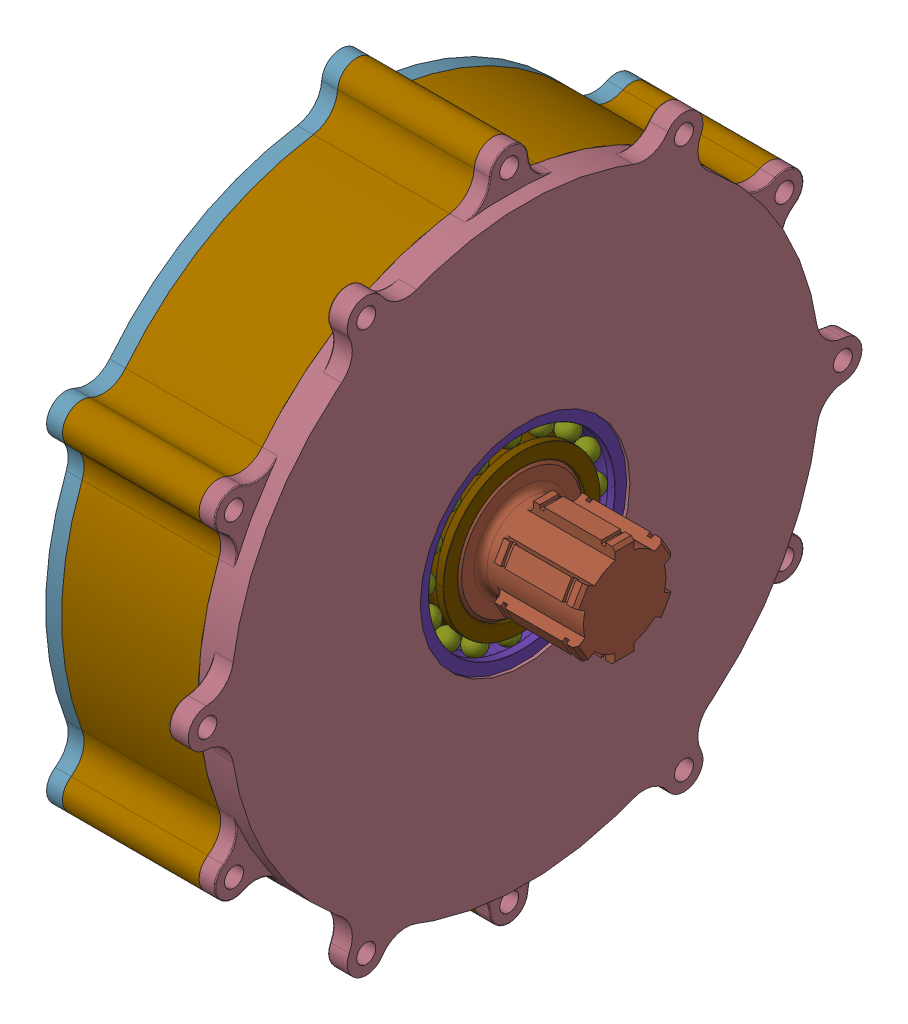
SolidWorks assembly A2490_Planetary_Gear_Set_Assembly, configuration 預設. Lengths in mm.
Overall size (102.6 212 212).
192 component instances, 24 part files, 41 mates.
Components (placement in the parent):
- planetary_gear_layout-1: planetary_gear_layout [預設] at origin
- A2490_Sun_Gear-1: A2490_Sun_Gear [預設] x (1 0 0) z (0 -0.792814 -0.609463) size (61.05 62.36 62.44)
- planet_gear_assembly-1: planet_gear_assembly [預設] at (0 56.25 0) x (1 0 0) z (0 0.754751 -0.656012) size (41 59.98 59.9)
  - A2490_Planet_Gear-1: A2490_Planet_Gear [預設] at origin size (30 59.98 59.9)
  - SKF_609-1: SKF_609 [Default] at (20.15 0 0) x (1 0 0) z (0 0.084929 0.996387) size (7 24 24)
    - SKF_609_12-1: SKF_609_12 [Default] x (1 0 0) z (0 -0.707107 0.707107) size (3.97 3.97 3.97)
    - SKF_609_12-2: SKF_609_12 [Default] x (1 0 0) z (0 -1 0) size (3.97 3.97 3.97)
    - SKF_609_12-3: SKF_609_12 [Default] x (1 0 0) z (0 -0.707107 -0.707107) size (3.97 3.97 3.97)
    - SKF_609_12-4: SKF_609_12 [Default] x (1 0 0) z (0 0 -1) size (3.97 3.97 3.97)
    - SKF_609_12-5: SKF_609_12 [Default] x (1 0 0) z (0 0.707107 -0.707107) size (3.97 3.97 3.97)
    - SKF_609_12-6: SKF_609_12 [Default] x (1 0 0) z (0 1 0) size (3.97 3.97 3.97)
    - SKF_609_12-7: SKF_609_12 [Default] x (1 0 0) z (0 0.707107 0.707107) size (3.97 3.97 3.97)
    - SKF_609_12-8: SKF_609_12 [Default] at origin size (3.97 3.97 3.97)
    - SKF_609_21-1: SKF_609_21 [Default] at origin size (7 24 24)
    - SKF_609_23-1: SKF_609_23 [Default] at origin size (7 14.45 14.45)
  - SKF_609-2: SKF_609 [Default] at (2.85 0 0) x (1 0 0) z (0 -0.037051 0.999313) size (7 24 24)
    - SKF_609_12-1: SKF_609_12 [Default] x (1 0 0) z (0 -0.707107 0.707107) size (3.97 3.97 3.97)
    - SKF_609_12-2: SKF_609_12 [Default] x (1 0 0) z (0 -1 0) size (3.97 3.97 3.97)
    - SKF_609_12-3: SKF_609_12 [Default] x (1 0 0) z (0 -0.707107 -0.707107) size (3.97 3.97 3.97)
    - SKF_609_12-4: SKF_609_12 [Default] x (1 0 0) z (0 0 -1) size (3.97 3.97 3.97)
    - SKF_609_12-5: SKF_609_12 [Default] x (1 0 0) z (0 0.707107 -0.707107) size (3.97 3.97 3.97)
    - SKF_609_12-6: SKF_609_12 [Default] x (1 0 0) z (0 1 0) size (3.97 3.97 3.97)
    - SKF_609_12-7: SKF_609_12 [Default] x (1 0 0) z (0 0.707107 0.707107) size (3.97 3.97 3.97)
    - SKF_609_12-8: SKF_609_12 [Default] at origin size (3.97 3.97 3.97)
    - SKF_609_21-1: SKF_609_21 [Default] at origin size (7 24 24)
    - SKF_609_23-1: SKF_609_23 [Default] at origin size (7 14.45 14.45)
  - WA701_retainingRing-1: WA701_retainingRing [預設] at (27.15 0 0) x (0 0 -1) z (1 0 0) size (25.9 24.75 1.2)
  - WA701_retainingRing-2: WA701_retainingRing [預設] at (1.65 0 0) x (0 0 -1) z (1 0 0) size (25.9 24.75 1.2)
  - A2490_Planet_Shaft-1: A2490_Planet_Shaft [預設] at (15 0 0) x (0 0 -1) z (1 0 0) size (11 11 41)
  - A2490_Planet_Spacer-1: A2490_Planet_Spacer [預設] at (27.15 0 0) x (0 -0.101105 -0.994876) z (1 0 0) size (12 12 3.85)
  - A2490_Planet_Spacer-2: A2490_Planet_Spacer [預設] at (-1 0 0) x (0 -0.111073 -0.993812) z (1 0 0) size (12 12 3.85)
- A2490_Ring_Housing-1: A2490_Ring_Housing [預設] at origin size (43 212 185.75)
- A2490_Carrier_Internal-1: A2490_Carrier_Internal [預設] at (-1 0 0) size (5 132.5 132.5)
- A2490_Carrier_Output-1: A2490_Carrier_Output [預設] at origin size (46.35 132.5 132.5)
- A2490_Carrer_Bridge-1: A2490_Carrer_Bridge [預設] at (15 28.125 -48.7139) size (32.6 16 16)
- A2490_Cap_Output-1: A2490_Cap_Output [預設] at origin size (15.8 212 212)
- A2490_Cap_Input-1: A2490_Cap_Input [預設] at origin size (10.8 212 185.75)
- A2490_Sun_Bearing_Spacer-1: A2490_Sun_Bearing_Spacer [預設] at (-7 0 0) size (2 27 27)
- SKF_16008-2: SKF_16008 [Default] at (36 0 0) size (9 68 68)
  - SKF_16008_20-1: SKF_16008_20 [Default] x (1 0 0) z (0 -0.382683 0.92388) size (6.35 6.35 6.35)
  - SKF_16008_20-2: SKF_16008_20 [Default] x (1 0 0) z (0 -0.707107 0.707107) size (6.35 6.35 6.35)
  - SKF_16008_20-3: SKF_16008_20 [Default] x (1 0 0) z (0 -0.92388 0.382683) size (6.35 6.35 6.35)
  - SKF_16008_20-4: SKF_16008_20 [Default] x (1 0 0) z (0 -1 0) size (6.35 6.35 6.35)
  - SKF_16008_20-5: SKF_16008_20 [Default] x (1 0 0) z (0 -0.92388 -0.382683) size (6.35 6.35 6.35)
  - SKF_16008_20-6: SKF_16008_20 [Default] x (1 0 0) z (0 -0.707107 -0.707107) size (6.35 6.35 6.35)
  - SKF_16008_20-7: SKF_16008_20 [Default] x (1 0 0) z (0 -0.382683 -0.92388) size (6.35 6.35 6.35)
  - SKF_16008_20-8: SKF_16008_20 [Default] x (1 0 0) z (0 0 -1) size (6.35 6.35 6.35)
  - SKF_16008_20-9: SKF_16008_20 [Default] x (1 0 0) z (0 0.382683 -0.92388) size (6.35 6.35 6.35)
  - SKF_16008_20-10: SKF_16008_20 [Default] x (1 0 0) z (0 0.707107 -0.707107) size (6.35 6.35 6.35)
  - SKF_16008_20-11: SKF_16008_20 [Default] x (1 0 0) z (0 0.92388 -0.382683) size (6.35 6.35 6.35)
  - SKF_16008_20-12: SKF_16008_20 [Default] x (1 0 0) z (0 1 0) size (6.35 6.35 6.35)
  - SKF_16008_20-13: SKF_16008_20 [Default] x (1 0 0) z (0 0.92388 0.382683) size (6.35 6.35 6.35)
  - SKF_16008_20-14: SKF_16008_20 [Default] x (1 0 0) z (0 0.707107 0.707107) size (6.35 6.35 6.35)
  - SKF_16008_20-15: SKF_16008_20 [Default] x (1 0 0) z (0 0.382683 0.92388) size (6.35 6.35 6.35)
  - SKF_16008_20-16: SKF_16008_20 [Default] at origin size (6.35 6.35 6.35)
  - SKF_16008_37-1: SKF_16008_37 [Default] at origin size (9 68 68)
  - SKF_16008_39-1: SKF_16008_39 [Default] at origin size (9 49.4 49.4)
- SKF_W_61705-1: SKF_W_61705 [Default] at (-5 0 0) x (1 0 0) z (0 0.081277 0.996692) size (4 32 32)
  - SKF_W_61705_25-1: SKF_W_61705_25 [Default] x (1 0 0) z (0 -0.294755 0.955573) size (1.59 1.59 1.59)
  - SKF_W_61705_25-2: SKF_W_61705_25 [Default] x (1 0 0) z (0 -0.56332 0.826239) size (1.59 1.59 1.59)
  - SKF_W_61705_25-3: SKF_W_61705_25 [Default] x (1 0 0) z (0 -0.781831 0.62349) size (1.59 1.59 1.59)
  - SKF_W_61705_25-4: SKF_W_61705_25 [Default] x (1 0 0) z (0 -0.930874 0.365341) size (1.59 1.59 1.59)
  - SKF_W_61705_25-5: SKF_W_61705_25 [Default] x (1 0 0) z (0 -0.997204 0.07473) size (1.59 1.59 1.59)
  - SKF_W_61705_25-6: SKF_W_61705_25 [Default] x (1 0 0) z (0 -0.974928 -0.222521) size (1.59 1.59 1.59)
  - SKF_W_61705_25-7: SKF_W_61705_25 [Default] x (1 0 0) z (0 -0.866025 -0.5) size (1.59 1.59 1.59)
  - SKF_W_61705_25-8: SKF_W_61705_25 [Default] x (1 0 0) z (0 -0.680173 -0.733052) size (1.59 1.59 1.59)
  - SKF_W_61705_25-9: SKF_W_61705_25 [Default] x (1 0 0) z (0 -0.433884 -0.900969) size (1.59 1.59 1.59)
  - SKF_W_61705_25-10: SKF_W_61705_25 [Default] x (1 0 0) z (0 -0.149042 -0.988831) size (1.59 1.59 1.59)
  - SKF_W_61705_25-11: SKF_W_61705_25 [Default] x (1 0 0) z (0 0.149042 -0.988831) size (1.59 1.59 1.59)
  - SKF_W_61705_25-12: SKF_W_61705_25 [Default] x (1 0 0) z (0 0.433884 -0.900969) size (1.59 1.59 1.59)
  - SKF_W_61705_25-13: SKF_W_61705_25 [Default] x (1 0 0) z (0 0.680173 -0.733052) size (1.59 1.59 1.59)
  - SKF_W_61705_25-14: SKF_W_61705_25 [Default] x (1 0 0) z (0 0.866025 -0.5) size (1.59 1.59 1.59)
  - SKF_W_61705_25-15: SKF_W_61705_25 [Default] x (1 0 0) z (0 0.974928 -0.222521) size (1.59 1.59 1.59)
  - SKF_W_61705_25-16: SKF_W_61705_25 [Default] x (1 0 0) z (0 0.997204 0.07473) size (1.59 1.59 1.59)
  - SKF_W_61705_25-17: SKF_W_61705_25 [Default] x (1 0 0) z (0 0.930874 0.365341) size (1.59 1.59 1.59)
  - SKF_W_61705_25-18: SKF_W_61705_25 [Default] x (1 0 0) z (0 0.781831 0.62349) size (1.59 1.59 1.59)
  - SKF_W_61705_25-19: SKF_W_61705_25 [Default] x (1 0 0) z (0 0.56332 0.826239) size (1.59 1.59 1.59)
  - SKF_W_61705_25-20: SKF_W_61705_25 [Default] x (1 0 0) z (0 0.294755 0.955573) size (1.59 1.59 1.59)
  - SKF_W_61705_25-21: SKF_W_61705_25 [Default] at origin size (1.59 1.59 1.59)
  - SKF_W_61705_47-1: SKF_W_61705_47 [Default] at origin size (4 32 32)
  - SKF_W_61705_49-1: SKF_W_61705_49 [Default] at origin size (4 27.35 27.35)
- SKF_W_61705-2: SKF_W_61705 [Default] at (-11 0 0) x (1 0 0) z (0 -0.925677 -0.378316) size (4 32 32)
  - SKF_W_61705_25-1: SKF_W_61705_25 [Default] x (1 0 0) z (0 -0.294755 0.955573) size (1.59 1.59 1.59)
  - SKF_W_61705_25-2: SKF_W_61705_25 [Default] x (1 0 0) z (0 -0.56332 0.826239) size (1.59 1.59 1.59)
  - SKF_W_61705_25-3: SKF_W_61705_25 [Default] x (1 0 0) z (0 -0.781831 0.62349) size (1.59 1.59 1.59)
  - SKF_W_61705_25-4: SKF_W_61705_25 [Default] x (1 0 0) z (0 -0.930874 0.365341) size (1.59 1.59 1.59)
  - SKF_W_61705_25-5: SKF_W_61705_25 [Default] x (1 0 0) z (0 -0.997204 0.07473) size (1.59 1.59 1.59)
  - SKF_W_61705_25-6: SKF_W_61705_25 [Default] x (1 0 0) z (0 -0.974928 -0.222521) size (1.59 1.59 1.59)
  - SKF_W_61705_25-7: SKF_W_61705_25 [Default] x (1 0 0) z (0 -0.866025 -0.5) size (1.59 1.59 1.59)
  - SKF_W_61705_25-8: SKF_W_61705_25 [Default] x (1 0 0) z (0 -0.680173 -0.733052) size (1.59 1.59 1.59)
  - SKF_W_61705_25-9: SKF_W_61705_25 [Default] x (1 0 0) z (0 -0.433884 -0.900969) size (1.59 1.59 1.59)
  - SKF_W_61705_25-10: SKF_W_61705_25 [Default] x (1 0 0) z (0 -0.149042 -0.988831) size (1.59 1.59 1.59)
  - SKF_W_61705_25-11: SKF_W_61705_25 [Default] x (1 0 0) z (0 0.149042 -0.988831) size (1.59 1.59 1.59)
  - SKF_W_61705_25-12: SKF_W_61705_25 [Default] x (1 0 0) z (0 0.433884 -0.900969) size (1.59 1.59 1.59)
  - SKF_W_61705_25-13: SKF_W_61705_25 [Default] x (1 0 0) z (0 0.680173 -0.733052) size (1.59 1.59 1.59)
  - SKF_W_61705_25-14: SKF_W_61705_25 [Default] x (1 0 0) z (0 0.866025 -0.5) size (1.59 1.59 1.59)
  - SKF_W_61705_25-15: SKF_W_61705_25 [Default] x (1 0 0) z (0 0.974928 -0.222521) size (1.59 1.59 1.59)
  - SKF_W_61705_25-16: SKF_W_61705_25 [Default] x (1 0 0) z (0 0.997204 0.07473) size (1.59 1.59 1.59)
  - SKF_W_61705_25-17: SKF_W_61705_25 [Default] x (1 0 0) z (0 0.930874 0.365341) size (1.59 1.59 1.59)
  - SKF_W_61705_25-18: SKF_W_61705_25 [Default] x (1 0 0) z (0 0.781831 0.62349) size (1.59 1.59 1.59)
  - SKF_W_61705_25-19: SKF_W_61705_25 [Default] x (1 0 0) z (0 0.56332 0.826239) size (1.59 1.59 1.59)
  - SKF_W_61705_25-20: SKF_W_61705_25 [Default] x (1 0 0) z (0 0.294755 0.955573) size (1.59 1.59 1.59)
  - SKF_W_61705_25-21: SKF_W_61705_25 [Default] at origin size (1.59 1.59 1.59)
  - SKF_W_61705_47-1: SKF_W_61705_47 [Default] at origin size (4 32 32)
  - SKF_W_61705_49-1: SKF_W_61705_49 [Default] at origin size (4 27.35 27.35)
- SKF_W_61705-3: SKF_W_61705 [Default] at (31 0 0) x (1 0 0) z (0 -0.694318 0.719668) size (4 32 32)
  - SKF_W_61705_25-1: SKF_W_61705_25 [Default] x (1 0 0) z (0 -0.294755 0.955573) size (1.59 1.59 1.59)
  - SKF_W_61705_25-2: SKF_W_61705_25 [Default] x (1 0 0) z (0 -0.56332 0.826239) size (1.59 1.59 1.59)
  - SKF_W_61705_25-3: SKF_W_61705_25 [Default] x (1 0 0) z (0 -0.781831 0.62349) size (1.59 1.59 1.59)
  - SKF_W_61705_25-4: SKF_W_61705_25 [Default] x (1 0 0) z (0 -0.930874 0.365341) size (1.59 1.59 1.59)
  - SKF_W_61705_25-5: SKF_W_61705_25 [Default] x (1 0 0) z (0 -0.997204 0.07473) size (1.59 1.59 1.59)
  - SKF_W_61705_25-6: SKF_W_61705_25 [Default] x (1 0 0) z (0 -0.974928 -0.222521) size (1.59 1.59 1.59)
  - SKF_W_61705_25-7: SKF_W_61705_25 [Default] x (1 0 0) z (0 -0.866025 -0.5) size (1.59 1.59 1.59)
  - SKF_W_61705_25-8: SKF_W_61705_25 [Default] x (1 0 0) z (0 -0.680173 -0.733052) size (1.59 1.59 1.59)
  - SKF_W_61705_25-9: SKF_W_61705_25 [Default] x (1 0 0) z (0 -0.433884 -0.900969) size (1.59 1.59 1.59)
  - SKF_W_61705_25-10: SKF_W_61705_25 [Default] x (1 0 0) z (0 -0.149042 -0.988831) size (1.59 1.59 1.59)
  - SKF_W_61705_25-11: SKF_W_61705_25 [Default] x (1 0 0) z (0 0.149042 -0.988831) size (1.59 1.59 1.59)
  - SKF_W_61705_25-12: SKF_W_61705_25 [Default] x (1 0 0) z (0 0.433884 -0.900969) size (1.59 1.59 1.59)
  - SKF_W_61705_25-13: SKF_W_61705_25 [Default] x (1 0 0) z (0 0.680173 -0.733052) size (1.59 1.59 1.59)
  - SKF_W_61705_25-14: SKF_W_61705_25 [Default] x (1 0 0) z (0 0.866025 -0.5) size (1.59 1.59 1.59)
  - SKF_W_61705_25-15: SKF_W_61705_25 [Default] x (1 0 0) z (0 0.974928 -0.222521) size (1.59 1.59 1.59)
  - SKF_W_61705_25-16: SKF_W_61705_25 [Default] x (1 0 0) z (0 0.997204 0.07473) size (1.59 1.59 1.59)
  - SKF_W_61705_25-17: SKF_W_61705_25 [Default] x (1 0 0) z (0 0.930874 0.365341) size (1.59 1.59 1.59)
  - SKF_W_61705_25-18: SKF_W_61705_25 [Default] x (1 0 0) z (0 0.781831 0.62349) size (1.59 1.59 1.59)
  - SKF_W_61705_25-19: SKF_W_61705_25 [Default] x (1 0 0) z (0 0.56332 0.826239) size (1.59 1.59 1.59)
  - SKF_W_61705_25-20: SKF_W_61705_25 [Default] x (1 0 0) z (0 0.294755 0.955573) size (1.59 1.59 1.59)
  - SKF_W_61705_25-21: SKF_W_61705_25 [Default] at origin size (1.59 1.59 1.59)
  - SKF_W_61705_47-1: SKF_W_61705_47 [Default] at origin size (4 32 32)
  - SKF_W_61705_49-1: SKF_W_61705_49 [Default] at origin size (4 27.35 27.35)
- A2490_o-rings_09170_35-1: A2490_o-rings_09170_35 [預設] at (33.7 0 0) x (0 0 1) z (-1 0 0) size (176 176 3)
- A2490_o-rings_09170_35-2: A2490_o-rings_09170_35 [預設] at (-4.7 0 0) x (0 0 1) z (-1 0 0) size (176 176 3)
- A2490_Motor_Flange-1: A2490_Motor_Flange [預設] at (45.35 -409.8417 1079.748) x (1 0 0) z (0 -0.09894 0.995093) size (12 95 95)
- A2490_Carrer_Bridge-2: A2490_Carrer_Bridge [預設] at (15 16.875 29.2284) x (1 0 0) z (0 -0.866025 -0.5) size (32.6 16 16) (suppressed, hidden)
- A2490_Carrer_Bridge-3: A2490_Carrer_Bridge [預設] at (15 -33.75 0) x (1 0 0) z (0 0.866025 -0.5) size (32.6 16 16) (suppressed, hidden)
- planet_gear_assembly-2: planet_gear_assembly [預設] at (0 -16.875 29.2284) x (1 0 0) z (0 0.190747 0.981639) size (41 59.98 59.9) (suppressed, hidden)
  - A2490_Planet_Gear-1: A2490_Planet_Gear [預設] at origin size (30 59.98 59.9)
  - SKF_609-1: SKF_609 [Default] at (20.15 0 0) x (1 0 0) z (0 0.084929 0.996387) size (7 24 24)
    - SKF_609_12-1: SKF_609_12 [Default] x (1 0 0) z (0 -0.707107 0.707107) size (3.97 3.97 3.97)
    - SKF_609_12-2: SKF_609_12 [Default] x (1 0 0) z (0 -1 0) size (3.97 3.97 3.97)
    - SKF_609_12-3: SKF_609_12 [Default] x (1 0 0) z (0 -0.707107 -0.707107) size (3.97 3.97 3.97)
    - SKF_609_12-4: SKF_609_12 [Default] x (1 0 0) z (0 0 -1) size (3.97 3.97 3.97)
    - SKF_609_12-5: SKF_609_12 [Default] x (1 0 0) z (0 0.707107 -0.707107) size (3.97 3.97 3.97)
    - SKF_609_12-6: SKF_609_12 [Default] x (1 0 0) z (0 1 0) size (3.97 3.97 3.97)
    - SKF_609_12-7: SKF_609_12 [Default] x (1 0 0) z (0 0.707107 0.707107) size (3.97 3.97 3.97)
    - SKF_609_12-8: SKF_609_12 [Default] at origin size (3.97 3.97 3.97)
    - SKF_609_21-1: SKF_609_21 [Default] at origin size (7 24 24)
    - SKF_609_23-1: SKF_609_23 [Default] at origin size (7 14.45 14.45)
  - SKF_609-2: SKF_609 [Default] at (2.85 0 0) x (1 0 0) z (0 -0.037051 0.999313) size (7 24 24)
    - SKF_609_12-1: SKF_609_12 [Default] x (1 0 0) z (0 -0.707107 0.707107) size (3.97 3.97 3.97)
    - SKF_609_12-2: SKF_609_12 [Default] x (1 0 0) z (0 -1 0) size (3.97 3.97 3.97)
    - SKF_609_12-3: SKF_609_12 [Default] x (1 0 0) z (0 -0.707107 -0.707107) size (3.97 3.97 3.97)
    - SKF_609_12-4: SKF_609_12 [Default] x (1 0 0) z (0 0 -1) size (3.97 3.97 3.97)
    - SKF_609_12-5: SKF_609_12 [Default] x (1 0 0) z (0 0.707107 -0.707107) size (3.97 3.97 3.97)
    - SKF_609_12-6: SKF_609_12 [Default] x (1 0 0) z (0 1 0) size (3.97 3.97 3.97)
    - SKF_609_12-7: SKF_609_12 [Default] x (1 0 0) z (0 0.707107 0.707107) size (3.97 3.97 3.97)
    - SKF_609_12-8: SKF_609_12 [Default] at origin size (3.97 3.97 3.97)
    - SKF_609_21-1: SKF_609_21 [Default] at origin size (7 24 24)
    - SKF_609_23-1: SKF_609_23 [Default] at origin size (7 14.45 14.45)
  - WA701_retainingRing-1: WA701_retainingRing [預設] at (27.15 0 0) x (0 0 -1) z (1 0 0) size (25.9 24.75 1.2)
  - WA701_retainingRing-2: WA701_retainingRing [預設] at (1.65 0 0) x (0 0 -1) z (1 0 0) size (25.9 24.75 1.2)
  - A2490_Planet_Shaft-1: A2490_Planet_Shaft [預設] at (15 0 0) x (0 0 -1) z (1 0 0) size (11 11 41)
  - A2490_Planet_Spacer-1: A2490_Planet_Spacer [預設] at (27.15 0 0) x (0 -0.101105 -0.994876) z (1 0 0) size (12 12 3.85)
  - A2490_Planet_Spacer-2: A2490_Planet_Spacer [預設] at (-1 0 0) x (0 -0.111073 -0.993812) z (1 0 0) size (12 12 3.85)
- planet_gear_assembly-3: planet_gear_assembly [預設] at (0 -16.875 -29.2284) x (1 0 0) z (0 -0.945498 -0.325627) size (41 59.98 59.9) (suppressed, hidden)
  - A2490_Planet_Gear-1: A2490_Planet_Gear [預設] at origin size (30 59.98 59.9)
  - SKF_609-1: SKF_609 [Default] at (20.15 0 0) x (1 0 0) z (0 0.084929 0.996387) size (7 24 24)
    - SKF_609_12-1: SKF_609_12 [Default] x (1 0 0) z (0 -0.707107 0.707107) size (3.97 3.97 3.97)
    - SKF_609_12-2: SKF_609_12 [Default] x (1 0 0) z (0 -1 0) size (3.97 3.97 3.97)
    - SKF_609_12-3: SKF_609_12 [Default] x (1 0 0) z (0 -0.707107 -0.707107) size (3.97 3.97 3.97)
    - SKF_609_12-4: SKF_609_12 [Default] x (1 0 0) z (0 0 -1) size (3.97 3.97 3.97)
    - SKF_609_12-5: SKF_609_12 [Default] x (1 0 0) z (0 0.707107 -0.707107) size (3.97 3.97 3.97)
    - SKF_609_12-6: SKF_609_12 [Default] x (1 0 0) z (0 1 0) size (3.97 3.97 3.97)
    - SKF_609_12-7: SKF_609_12 [Default] x (1 0 0) z (0 0.707107 0.707107) size (3.97 3.97 3.97)
    - SKF_609_12-8: SKF_609_12 [Default] at origin size (3.97 3.97 3.97)
    - SKF_609_21-1: SKF_609_21 [Default] at origin size (7 24 24)
    - SKF_609_23-1: SKF_609_23 [Default] at origin size (7 14.45 14.45)
  - SKF_609-2: SKF_609 [Default] at (2.85 0 0) x (1 0 0) z (0 -0.037051 0.999313) size (7 24 24)
    - SKF_609_12-1: SKF_609_12 [Default] x (1 0 0) z (0 -0.707107 0.707107) size (3.97 3.97 3.97)
    - SKF_609_12-2: SKF_609_12 [Default] x (1 0 0) z (0 -1 0) size (3.97 3.97 3.97)
    - SKF_609_12-3: SKF_609_12 [Default] x (1 0 0) z (0 -0.707107 -0.707107) size (3.97 3.97 3.97)
    - SKF_609_12-4: SKF_609_12 [Default] x (1 0 0) z (0 0 -1) size (3.97 3.97 3.97)
    - SKF_609_12-5: SKF_609_12 [Default] x (1 0 0) z (0 0.707107 -0.707107) size (3.97 3.97 3.97)
    - SKF_609_12-6: SKF_609_12 [Default] x (1 0 0) z (0 1 0) size (3.97 3.97 3.97)
    - SKF_609_12-7: SKF_609_12 [Default] x (1 0 0) z (0 0.707107 0.707107) size (3.97 3.97 3.97)
    - SKF_609_12-8: SKF_609_12 [Default] at origin size (3.97 3.97 3.97)
    - SKF_609_21-1: SKF_609_21 [Default] at origin size (7 24 24)
    - SKF_609_23-1: SKF_609_23 [Default] at origin size (7 14.45 14.45)
  - WA701_retainingRing-1: WA701_retainingRing [預設] at (27.15 0 0) x (0 0 -1) z (1 0 0) size (25.9 24.75 1.2)
  - WA701_retainingRing-2: WA701_retainingRing [預設] at (1.65 0 0) x (0 0 -1) z (1 0 0) size (25.9 24.75 1.2)
  - A2490_Planet_Shaft-1: A2490_Planet_Shaft [預設] at (15 0 0) x (0 0 -1) z (1 0 0) size (11 11 41)
  - A2490_Planet_Spacer-1: A2490_Planet_Spacer [預設] at (27.15 0 0) x (0 -0.101105 -0.994876) z (1 0 0) size (12 12 3.85)
  - A2490_Planet_Spacer-2: A2490_Planet_Spacer [預設] at (-1 0 0) x (0 -0.111073 -0.993812) z (1 0 0) size (12 12 3.85)
Mates (geometry in assembly coordinates):
- Concentric1: concentric aligned: circle of planetary_gear_layout-1; circle of A2490_Planet_Gear-1
- Coincident14: coincident aligned: plane of planet_gear_assembly-1 through (0 56.25 0) normal (1 0 0)
- Concentric2: concentric aligned: circle of planetary_gear_layout-1; circle of A2490_Sun_Gear-1
- Coincident15: coincident aligned: plane of A2490_Sun_Gear-1 through (0 0 0) normal (1 0 0)
- GearMate2: gear = 23000 : 22000 mm: line of planet_gear_assembly-1/A2490_Planet_Gear-1 through (30 56.25 0) axis (-1 0 0); line of A2490_Sun_Gear-1 through (30 0 0) axis (-1 0 0)
- Coincident16: coincident anti-aligned: plane of A2490_Ring_Housing-1 through (0 0 0) normal (-1 0 0)
- Concentric3: concentric anti-aligned: cylinder of planetary_gear_layout-1; cylinder of A2490_Ring_Housing-1 through (30 0 0) axis (-1 0 0) radius 92.875
- Coincident17: coincident aligned: plane of A2490_Ring_Housing-1 through (0 0 0) normal (0 1 0)
- Coincident18: coincident anti-aligned: plane of planet_gear_assembly-1/A2490_Planet_Shaft-1 through (-1 53.2979 -3.3964) normal (-1 0 0); plane of A2490_Carrier_Internal-1 through (-1 0 0) normal (1 0 0)
- Concentric4: concentric aligned: circle of planetary_gear_layout-1; cylinder of A2490_Carrier_Internal-1 through (-6 0 0) axis (1 0 0) radius 16
- Concentric5: concentric aligned: circle of planetary_gear_layout-1; cylinder of A2490_Carrier_Internal-1 through (-14.4853 56.25 0) axis (1 0 0) radius 3
- Concentric6: concentric anti-aligned: cylinder of A2490_Cap_Output-1 through (46 0 0) axis (-1 0 0) radius 34; cylinder of SKF_16008-1/SKF_16008_37-1 through (86 0 0) axis (1 0 0) radius 34
- Coincident19: coincident aligned: plane of A2490_Carrier_Output-1 through (45 0 0) normal (1 0 0); plane of SKF_16008-1/SKF_16008_37-1 through (45 29.4 0) normal (1 0 0)
- Concentric7: concentric aligned: cylinder of A2490_Cap_Input-1 through (-14 0 0) axis (1 0 0) radius 26; cylinder of SKF_61808-1/SKF_61808_47-1 through (36 0 0) axis (1 0 0) radius 26
- Coincident20: coincident aligned: plane of A2490_Cap_Input-1 through (-14 0 0) normal (-1 0 0); plane of SKF_61808-1/SKF_61808_47-1 through (-14 25.7 0) normal (-1 0 0)
- Concentric8: concentric anti-aligned: cylinder of A2490_Sun_Gear-1 through (30.002 0 0) axis (-1 0 0) radius 12.5; cylinder of SKF_61806-1/SKF_61806_41-1 through (92 0 0) axis (1 0 0) radius 15
- Coincident21: coincident aligned: plane of A2490_Carrier_Internal-1 through (-1 0 0) normal (1 0 0); plane of SKF_61806-1/SKF_61806_39-1 through (-1 19.375 0) normal (1 0 0)
- Concentric9: concentric anti-aligned: cylinder of A2490_Sun_Gear-1 through (30.002 0 0) axis (-1 0 0) radius 12.5; cylinder of SKF_61806-2/SKF_61806_41-1 through (87 0 0) axis (1 0 0) radius 15
- Concentric10: concentric aligned: cylinder of A2490_Cap_Output-1 through (41 -50 -86.6025) axis (-1 0 0) radius 3; cylinder of hex flange screw_am-1 through (33.1 -30.5 -52.8275) axis (-1 0 0) radius 3
- Coincident23: coincident anti-aligned: plane of A2490_Cap_Output-1 through (36 0 0) normal (-1 0 0); plane of hex flange screw_am-1 through (40 -25.8812 -52.8275) normal (1 0 0)
- Concentric11: concentric anti-aligned: cylinder of hex flange screw_am-1 through (33.1 -30.5 -52.8275) axis (-1 0 0) radius 3; cylinder of hex flange nut_am-1 through (23.9625 -30.5 -52.8275) axis (1 0 0) radius 3
- Coincident24: coincident anti-aligned: plane of A2490_Cap_Output-1 through (41 0 0) normal (1 0 0); plane of hex flange nut_am-1 through (43 -30.5 -42.8275) normal (-1 0 0)
- Concentric12: concentric anti-aligned: cylinder of A2490_Sun_Gear-1 through (30.002 0 0) axis (-1 0 0) radius 12.5; cylinder of SKF_W_61705-1/SKF_W_61705_49-1 through (45 0 0) axis (1 0 0) radius 12.5
- Coincident25: coincident aligned: plane of A2490_Carrier_Internal-1 through (-1 0 0) normal (1 0 0); plane of SKF_W_61705-1/SKF_W_61705_47-1 through (-1 15.0949 -1.2309) normal (1 0 0)
- Concentric13: concentric anti-aligned: cylinder of A2490_Sun_Gear-1 through (30.002 0 0) axis (-1 0 0) radius 12.5; cylinder of SKF_W_61705-2/SKF_W_61705_49-1 through (39 0 0) axis (1 0 0) radius 12.5
- Coincident26: coincident aligned: plane of A2490_Cap_Input-1 through (-7 0 0) normal (1 0 0); plane of SKF_W_61705-2/SKF_W_61705_47-1 through (-7 -5.7296 14.0194) normal (1 0 0)
- Concentric14: concentric aligned: cylinder of A2490_Carrier_Output-1 through (31.3 28.125 -48.7139) axis (-1 0 0) radius 8.05; cylinder of A2490_Carrer_Bridge-1 through (31.3 28.125 -48.7139) axis (-1 0 0) radius 8
- Coincident27: coincident anti-aligned: plane of A2490_Carrier_Internal-1 through (-1.3 0 0) normal (1 0 0); plane of A2490_Carrer_Bridge-1 through (-1.3 28.125 -48.7139) normal (-1 0 0)
- Concentric15: concentric aligned: cylinder of A2490_Sun_Gear-1 through (30.002 0 0) axis (-1 0 0) radius 12.5; cylinder of A2490_Sun_Bearing_Spacer-1 through (-5 0 0) axis (-1 0 0) radius 12.5
- Coincident28: coincident anti-aligned: plane of SKF_W_61705-1/SKF_W_61705_49-1 through (-5 13.5899 -1.1082) normal (-1 0 0); plane of A2490_Sun_Bearing_Spacer-1 through (-5 0 0) normal (1 0 0)
- Concentric16: concentric aligned: cylinder of A2490_Cap_Input-1 through (-1.2 0 0) axis (-1 0 0) radius 88; line of o-rings_am-1 through (0 6.1164 -1.491) axis (0 0 -1)
- Concentric17: concentric anti-aligned: cylinder of A2490_Sun_Gear-1 through (-12.35 0 0) axis (1 0 0) radius 11.95; cylinder of WA703_retainingRing-1 through (-11 0 0) axis (-1 0 0) radius 11.6
- Coincident29: coincident anti-aligned: plane of A2490_Sun_Gear-1 through (-11 0 0) normal (-1 0 0); plane of WA703_retainingRing-1 through (-11 0 0) normal (1 0 0)
- Concentric18: concentric anti-aligned: cylinder of A2490_Sun_Gear-1 through (35.8 0 0) axis (-1 0 0) radius 12.5; cylinder of SKF_W_61705-3/SKF_W_61705_49-1 through (81 0 0) axis (1 0 0) radius 12.5
- Coincident30: coincident anti-aligned: plane of A2490_Sun_Gear-1 through (31 0 0) normal (1 0 0); plane of SKF_W_61705-3/SKF_W_61705_49-1 through (31 9.8127 9.467) normal (-1 0 0)
- Concentric23: concentric aligned: cylinder of A2490_Sun_Gear-1 through (-25.25 0 0) axis (1 0 0) radius 10; cylinder of A2490_Motor_Flange-1 through (-25.25 0 0) axis (1 0 0) radius 8.25
- Coincident31: coincident anti-aligned: plane of A2490_Sun_Gear-1 through (-13.25 0 0) normal (-1 0 0); plane of A2490_Motor_Flange-1 through (-13.25 -409.8417 1079.748) normal (1 0 0)
- Concentric24: concentric anti-aligned: cylinder of A2490_Cap_Output-1 through (31.2 0 0) axis (1 0 0) radius 85.6; line of A2490_o-rings_09170_3^A2490_Planetary_Gear_Set_Assembly_m2_5-1 through (0 3.3 35.35) axis (0 0 -1)
- Distance1: distance = 1.5 mm aligned: plane of A2490_o-rings_09170_3^A2490_Planetary_Gear_Set_Assembly_m2_5-1 through (33.7 0 0) normal (-1 0 0); plane of A2490_Cap_Output-1 through (35.2 0 0) normal (-1 0 0)
- Concentric25: concentric aligned: cylinder of A2490_Cap_Input-1 through (-2.2 0 0) axis (-1 0 0) radius 85.6; line of A2490_o-rings_09170_35-2 through (0 3.3 -3.05) axis (0 0 -1)
- Distance2: distance = 1.5 mm anti-aligned: plane of A2490_o-rings_09170_35-2 through (-4.7 0 0) normal (-1 0 0); plane of A2490_Cap_Input-1 through (-6.2 0 0) normal (1 0 0)
